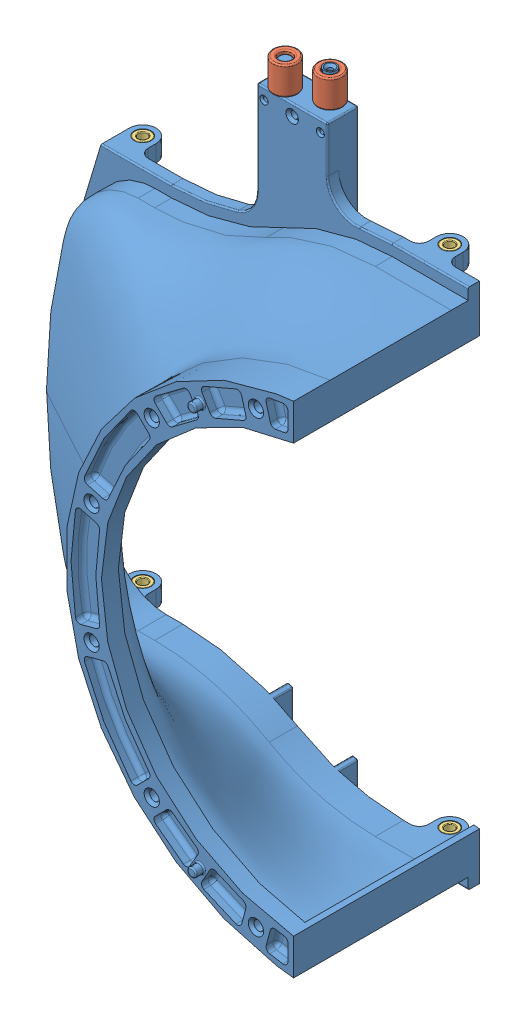
SolidWorks assembly HDT, configuration Default. Lengths in mm.
Overall size (142.99 257 79.76).
9 component instances, 3 part files, 17 mates.
Components (placement in the parent):
- D_terminator_extend_to_hinge_v2-1: D_terminator_extend_to_hinge_v2 [Default] at origin size (142.99 257 79.76)
- h_cam_sleeve-1: h_cam_sleeve [Default] at (-64.5 118 -3.4495) x (-0.808004 0 0.589177) z (-0.589177 0 -0.808004) size (8.75 10 8.75)
- h_cam_sleeve-2: h_cam_sleeve [Default] at (-64.5 -128 -3.4495) x (-0.808274 0 0.588807) z (-0.588807 0 -0.808274) size (8.75 10 8.75)
- h_cam_sleeve-3: h_cam_sleeve [Default] at (-76.5 118 0.4495) x (0.999095 0 0.04253) z (-0.04253 0 0.999095) size (8.75 10 8.75)
- h_cam_sleeve-4: h_cam_sleeve [Default] at (-76.5 -128 0.4495) x (0.988075 0 -0.153973) z (0.153973 0 0.988075) size (8.75 10 8.75)
- hinge_bushing-1: hinge_bushing [Default] at (-24.5395 86.6314 -6) size (6 6 6)
- hinge_bushing-2: hinge_bushing [Default] at (-133.5395 65.5 -6) size (6 6 6)
- hinge_bushing-3: hinge_bushing [Default] at (-133.5395 -71.5 -6) size (6 6 6)
- hinge_bushing-4: hinge_bushing [Default] at (-24.5395 -92.6314 -6) size (6 6 6)
Mates (geometry in assembly coordinates):
- Coincident1: coordinate: point of D_terminator_extend_to_hinge_v2-1; point of assembly
- Coincident6: coincident anti-aligned: plane of D_terminator_extend_to_hinge_v2-1 through (-58 118 -7) normal (0 1 0); plane of h_cam_sleeve-1 through (-64.5 118 -3.4495) normal (0 -1 0)
- Coincident7: coincident anti-aligned: plane of D_terminator_extend_to_hinge_v2-1 through (-58 -118 -7) normal (0 -1 0); plane of h_cam_sleeve-2 through (-64.5 -118 -3.4495) normal (0 1 0)
- Coincident9: coincident anti-aligned: plane of D_terminator_extend_to_hinge_v2-1 through (-58 -118 -7) normal (0 -1 0); plane of h_cam_sleeve-4 through (-76.5 -118 0.4495) normal (0 1 0)
- Coincident11: coincident anti-aligned: plane of D_terminator_extend_to_hinge_v2-1 through (-58 118 -7) normal (0 1 0); plane of h_cam_sleeve-3 through (-76.5 118 0.4495) normal (0 -1 0)
- Concentric15: concentric anti-aligned: cylinder of D_terminator_extend_to_hinge_v2-1 through (-24.5395 86.6314 -6) axis (0 1 0) radius 3; cylinder of hinge_bushing-1 through (-24.5395 92.6314 -6) axis (0 -1 0) radius 3
- Coincident13: coincident aligned: plane of D_terminator_extend_to_hinge_v2-1 through (-8 92.6314 4) normal (0 1 0); plane of hinge_bushing-1 through (-24.5395 92.6314 -6) normal (0 1 0)
- Coincident14: coincident aligned: plane of D_terminator_extend_to_hinge_v2-1 through (-113.302 71.5 4) normal (0 1 0); plane of hinge_bushing-2 through (-133.5395 71.5 -6) normal (0 1 0)
- Concentric16: concentric anti-aligned: cylinder of D_terminator_extend_to_hinge_v2-1 through (-133.5395 65.5 -6) axis (0 1 0) radius 3; cylinder of hinge_bushing-2 through (-133.5395 71.5 -6) axis (0 -1 0) radius 1.625
- Concentric17: concentric aligned: cylinder of D_terminator_extend_to_hinge_v2-1 through (-133.5395 -65.5 -6) axis (0 -1 0) radius 3; cylinder of hinge_bushing-3 through (-133.5395 -65.5 -6) axis (0 -1 0) radius 1.625
- Coincident15: coincident aligned: plane of D_terminator_extend_to_hinge_v2-1 through (-138.302 -65.5 -10.7625) normal (0 1 0); plane of hinge_bushing-3 through (-133.5395 -65.5 -6) normal (0 1 0)
- Concentric18: concentric aligned: cylinder of D_terminator_extend_to_hinge_v2-1 through (-24.5395 -86.6314 -6) axis (0 -1 0) radius 3; cylinder of hinge_bushing-4 through (-24.5395 -86.6314 -6) axis (0 -1 0) radius 3
- Coincident16: coincident aligned: plane of D_terminator_extend_to_hinge_v2-1 through (-8 -86.6314 4) normal (0 1 0); plane of hinge_bushing-4 through (-24.5395 -86.6314 -6) normal (0 1 0)
- Concentric19: concentric aligned: cylinder of D_terminator_extend_to_hinge_v2-1 through (-64.5 127 -3.4495) axis (0 -1 0) radius 2.2; cylinder of h_cam_sleeve-1 through (-64.5 128 -3.4495) axis (0 -1 0) radius 2.3
- Concentric20: concentric aligned: cylinder of D_terminator_extend_to_hinge_v2-1 through (-76.5 127 0.4495) axis (0 -1 0) radius 2.2; cylinder of h_cam_sleeve-3 through (-76.5 128 0.4495) axis (0 -1 0) radius 2.3
- Concentric21: concentric anti-aligned: cylinder of D_terminator_extend_to_hinge_v2-1 through (-76.5 -127 0.4495) axis (0 1 0) radius 2.2; cylinder of h_cam_sleeve-4 through (-76.5 -118 0.4495) axis (0 -1 0) radius 2.3
- Concentric22: concentric anti-aligned: cylinder of D_terminator_extend_to_hinge_v2-1 through (-64.5 -127 -3.4495) axis (0 1 0) radius 2.2; cylinder of h_cam_sleeve-2 through (-64.5 -118 -3.4495) axis (0 -1 0) radius 2.3
